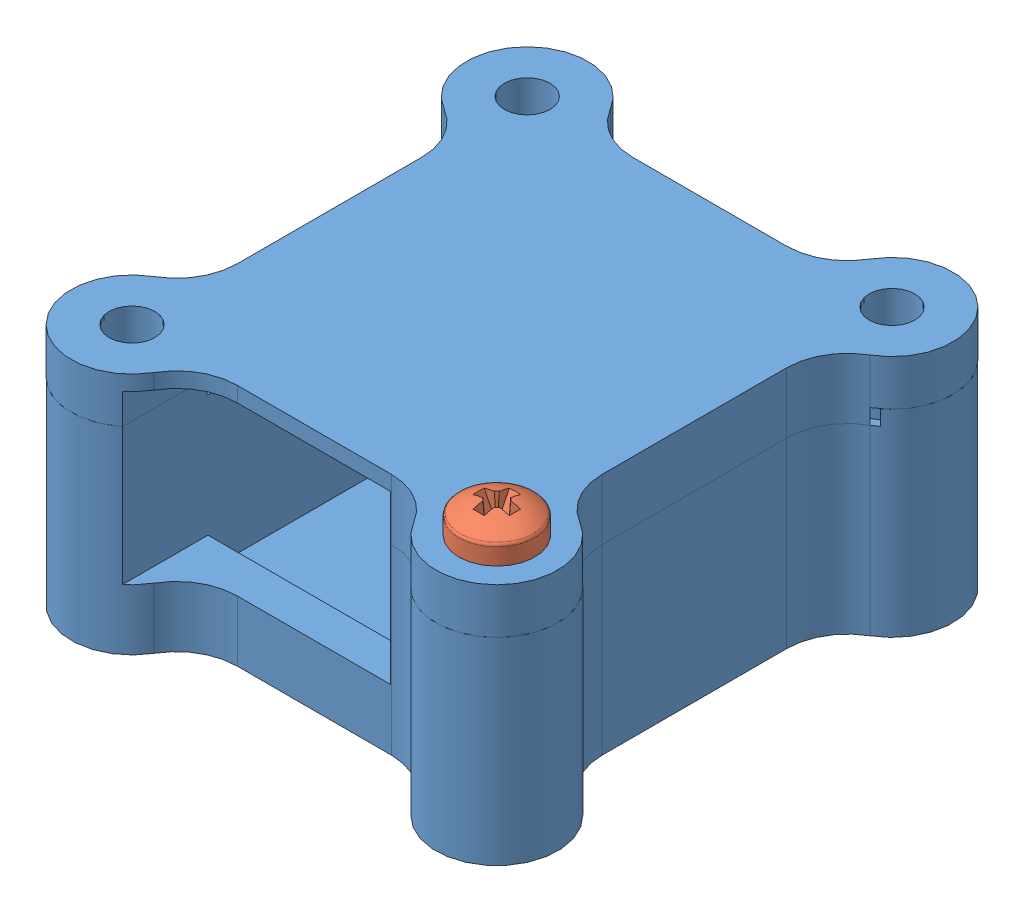
SolidWorks assembly dcdc_enclosure_assembly, configuration Default. Lengths in mm.
Overall size (32 18.05 34).
6 component instances, 2 part files, 11 mates.
Components (placement in the parent):
- dcdc_enclosure-1: dcdc_enclosure [bottom] at (8.8588 8.8771 30.0673) size (32 13 34)
- dcdc_enclosure-2: dcdc_enclosure [top] at (8.8588 20.8771 30.0673) size (32 5 34)
- pan head cross recess screw_iso-8: pan head cross recess screw_iso [ISO 7045 - M2.5 x 3 - Z - 3N] at (20.8588 26.9771 43.0673) x (0 -1 0) z (0 0 1) size (5.05 5 5)
- pan head cross recess screw_iso-9: pan head cross recess screw_iso [ISO 7045 - M2.5 x 3 - Z - 3N] at (-3.1412 26.9771 43.0673) x (0 -1 0) z (0 0 1) size (5.05 5 5)
- pan head cross recess screw_iso-10: pan head cross recess screw_iso [ISO 7045 - M2.5 x 3 - Z - 3N] at (20.8588 26.9771 17.0673) x (0 -1 0) z (0 0 1) size (5.05 5 5)
- pan head cross recess screw_iso-11: pan head cross recess screw_iso [ISO 7045 - M2.5 x 3 - Z - 3N] at (-3.1412 26.9771 17.0673) x (0 -1 0) z (0 0 1) size (5.05 5 5)
Mates (geometry in assembly coordinates):
- Concentric1: concentric aligned: cylinder of dcdc_enclosure-1 through (-3.1412 20.8771 43.0673) axis (0 -1 0) radius 4; cylinder of dcdc_enclosure-2 through (-3.1412 24.8771 43.0673) axis (0 -1 0) radius 4
- Concentric2: concentric aligned: cylinder of dcdc_enclosure-1 through (20.8588 20.8771 17.0673) axis (0 -1 0) radius 4; cylinder of dcdc_enclosure-2 through (20.8588 24.8771 17.0673) axis (0 -1 0) radius 4
- Coincident1: coincident anti-aligned: plane of dcdc_enclosure-1 through (20.8588 20.8771 17.0673) normal (0 1 0); plane of dcdc_enclosure-2 through (20.8588 20.8771 17.0673) normal (0 -1 0)
- Concentric9: concentric aligned: cylinder of dcdc_enclosure-2 through (20.8588 20.8771 43.0673) axis (0 1 0) radius 1.5; cylinder of pan head cross recess screw_iso-8 through (20.8588 52.3771 43.0673) axis (0 1 0) radius 2.5
- Coincident7: coincident anti-aligned: plane of dcdc_enclosure-2 through (20.8588 24.8771 17.0673) normal (0 1 0); plane of pan head cross recess screw_iso-8 through (22.1088 24.8771 43.0673) normal (0 -1 0)
- Concentric10: concentric aligned: cylinder of dcdc_enclosure-2 through (-3.1412 20.8771 43.0673) axis (0 1 0) radius 1.5; cylinder of pan head cross recess screw_iso-9 through (-3.1412 52.3771 43.0673) axis (0 1 0) radius 2.5
- Coincident8: coincident anti-aligned: plane of dcdc_enclosure-2 through (20.8588 24.8771 17.0673) normal (0 1 0); plane of pan head cross recess screw_iso-9 through (-1.8912 24.8771 43.0673) normal (0 -1 0)
- Concentric11: concentric aligned: cylinder of dcdc_enclosure-2 through (20.8588 20.8771 17.0673) axis (0 1 0) radius 1.5; cylinder of pan head cross recess screw_iso-10 through (20.8588 52.3771 17.0673) axis (0 1 0) radius 2.5
- Coincident9: coincident anti-aligned: plane of dcdc_enclosure-2 through (20.8588 24.8771 17.0673) normal (0 1 0); plane of pan head cross recess screw_iso-10 through (22.1088 24.8771 17.0673) normal (0 -1 0)
- Concentric12: concentric aligned: cylinder of dcdc_enclosure-2 through (-3.1412 20.8771 17.0673) axis (0 1 0) radius 1.5; cylinder of pan head cross recess screw_iso-11 through (-3.1412 52.3771 17.0673) axis (0 1 0) radius 2.5
- Coincident10: coincident anti-aligned: plane of dcdc_enclosure-2 through (20.8588 24.8771 17.0673) normal (0 1 0); plane of pan head cross recess screw_iso-11 through (-1.8912 24.8771 17.0673) normal (0 -1 0)
